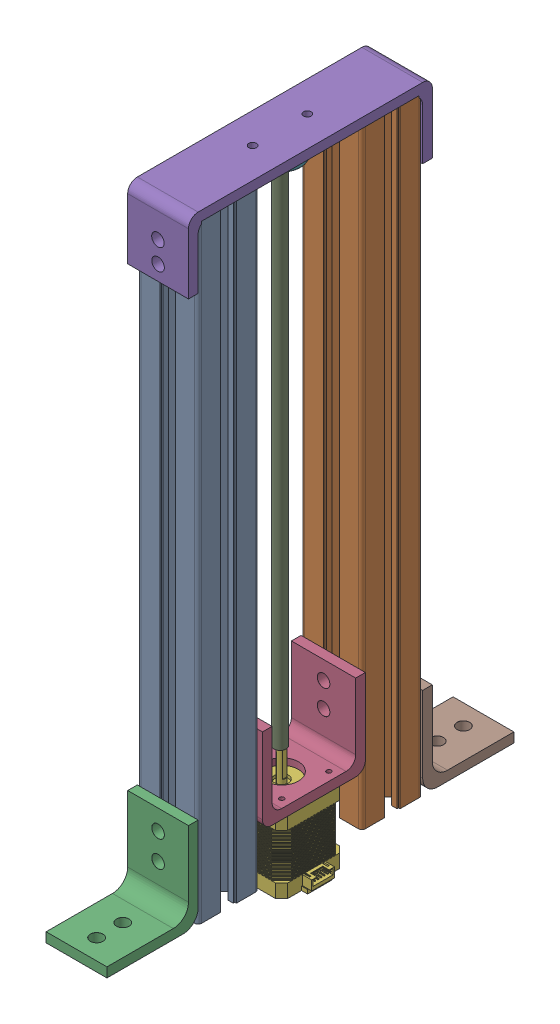
SolidWorks assembly Z_axis, configuration Default. Lengths in mm.
Overall size (48.4 418.35 267.7).
9 component instances, 7 part files, 18 mates.
Components (placement in the parent):
- AlShort-1: AlShort [Default] at (447.9758 386.6445 41.439) x (0 0 -1) z (0 -1 0) size (40 40 400)
- AlShort-2: AlShort [Default] at (447.9758 386.6445 -66.261) x (0 0 -1) z (0 -1 0) size (40 40 400)
- LBracket-1: LBracket [Default] at (444.3801 -13.3555 103.0519) x (0 0 -1) z (1 0 0) size (60 60 40)
- ZStepperHolder-1: ZStepperHolder [Default] at (427.9758 21.6445 8.739) x (0 0 -1) z (1 0 0) size (67.7 56.35 42.3)
- ZTopBracket-1: ZTopBracket [Default] at (467.9758 392.9945 67.789) x (0 0 1) z (1 0 0) size (160.4 46.35 40)
- Stepper-1: Stepper [Default] at (449.0758 -25.3555 -12.361) size (48.4 67.5 42.2)
- KFL08-1: KFL08 [Default] at (447.9758 386.6445 -12.411) x (-1 0 0) z (0 0 1) size (27 12 48)
- LBracket-2: LBracket [Default] at (451.5715 -13.3555 -127.8739) x (0 0 1) z (-1 0 0) size (60 60 40)
- LinearRod-1: LinearRod [Default] at (447.9758 42.1445 -12.411) size (8 332.5 8)
Mates (geometry in assembly coordinates):
- Coincident32: coincident anti-aligned: plane of AlShort-1 through (430.2258 -13.3555 61.439) normal (0 0 1); plane of LBracket-1 through (427.9758 -7.0055 61.439) normal (0 0 -1)
- Coincident37: coincident anti-aligned: plane of AlShort-1 through (465.7258 -13.3555 21.439) normal (0 0 -1); plane of ZStepperHolder-1 through (427.9758 33.6445 21.439) normal (0 0 1)
- Coincident35: coincident anti-aligned: plane of AlShort-2 through (430.2258 -13.3555 -46.261) normal (0 0 1); plane of ZStepperHolder-1 through (427.9758 33.6445 -46.261) normal (0 0 -1)
- Coincident36: coincident aligned: plane of AlShort-2 through (427.9758 -13.3555 -61.111) normal (-1 0 0); plane of ZStepperHolder-1 through (427.9758 39.9945 8.739) normal (-1 0 0)
- Coincident39: coincident anti-aligned: plane of AlShort-2 through (443.8669 386.6445 -59.611) normal (0 1 0); plane of ZTopBracket-1 through (467.9758 386.6445 67.789) normal (0 -1 0)
- Coincident40: coincident anti-aligned: plane of AlShort-2 through (465.7258 -13.3555 -86.261) normal (0 0 -1); plane of ZTopBracket-1 through (427.9758 346.6445 -86.261) normal (0 0 1)
- Coincident41: coincident aligned: plane of AlShort-2 through (467.9758 -13.3555 -61.111) normal (1 0 0); plane of ZTopBracket-1 through (467.9758 386.6445 -86.261) normal (1 0 0)
- Coincident43: coincident aligned: plane of AlShort-2 through (427.9758 -13.3555 -61.111) normal (-1 0 0); plane of Stepper-1 through (427.9758 33.6445 -29.462) normal (-1 0 0)
- Coincident47: coincident anti-aligned: plane of AlShort-2 through (430.2258 -13.3555 -86.261) normal (0 0 -1); plane of LBracket-2 through (467.9758 -7.0055 -86.261) normal (0 0 1)
- Coincident49: coincident aligned: plane of AlShort-2 through (467.9758 -13.3555 -71.411) normal (1 0 0); plane of LBracket-2 through (467.9758 -7.0055 -146.261) normal (1 0 0)
- Coincident44: coincident anti-aligned: plane of ZStepperHolder-1 through (427.9758 33.6445 8.739) normal (0 -1 0); plane of Stepper-1 through (449.0758 33.6445 -12.361) normal (0 1 0)
- Parallel1: parallel anti-aligned: cylinder of ZStepperHolder-1 through (449.1258 33.6445 -12.411) axis (0 1 0) radius 11; cylinder of Stepper-1 through (449.0758 35.6445 -12.361) axis (0 -1 0) radius 11
- Parallel2: parallel aligned: line of ZStepperHolder-1 through (470.2758 39.9945 -33.561) axis (-1 0 0); line of Stepper-1 through (466.1768 33.6445 -33.461) axis (-1 0 0)
- Coincident62: coincident: line of ZStepperHolder-1 through (427.9758 39.9945 8.739) axis (1 0 0); plane of Stepper-1 through (431.9748 33.6445 8.739) normal (0 0 1)
- Coincident45: coincident anti-aligned: plane of ZTopBracket-1 through (467.9758 386.6445 67.789) normal (0 -1 0); plane of KFL08-1 through (447.9758 386.6445 -12.411) normal (0 1 0)
- Concentric1: concentric anti-aligned: cylinder of ZTopBracket-1 through (447.9758 426.6445 -30.411) axis (0 -1 0) radius 2.5; cylinder of KFL08-1 through (447.9758 382.6445 -30.411) axis (0 1 0) radius 2.5
- Coincident66: coincident anti-aligned: plane of Stepper-1 through (449.0758 54.1445 -12.361) normal (0 1 0); plane of LinearRod-1 through (435.4964 54.0429 12.5036) normal (0 -1 0)
- Coincident67: coincident anti-aligned: circle of KFL08-1; circle of LinearRod-1
